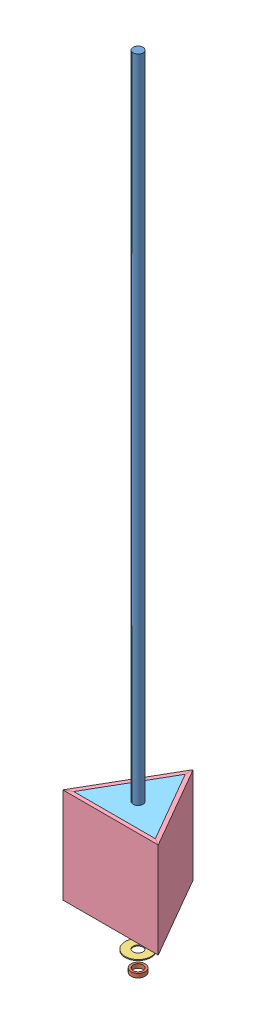
SolidWorks assembly rod_exploded, configuration Default. Lengths in mm.
Overall size (348 2551.69 364.2).
15 component instances, 6 part files, 3 mates.
Components (placement in the parent):
- rod-1: rod [Default] at (977.2141 709.9151 2218.518) size (31.75 2438.4 31.75)
- collar-1: collar [Default] at (977.2141 596.6255 2218.518) size (44.45 12.7 44.45)
- washer-1: washer [Default] at (977.2141 657.9856 2218.518) size (82.55 3.17 82.55)
- triangle-1: triangle [Default] at (859.8458 526.0056 2574.5415) x (1 0 0) z (0 1 0) size (348 364.2 304.8)
  - triangle_face-1: triangle_face [Default] at (-35.0317 268.0353 238.4474) size (304.8 12.7 304.8)
  - triangle_face-2: triangle_face [Default] at (117.3683 531.9998 238.4474) x (-0.5 -0.866025 0) z (0 0 1) size (304.8 12.7 304.8)
  - triangle_face-3: triangle_face [Default] at (269.7683 268.0353 238.4474) x (-0.5 0.866025 0) z (0 0 1) size (304.8 12.7 304.8)
  - triangle_top_bot-1: triangle_top_bot [Default] at (269.7683 268.0353 238.4474) x (0.5 -0.866025 0) z (0 0 -1) size (260.81 225.86 12.7)
  - triangle_top_bot-2: triangle_top_bot [Default] at (269.7683 268.0353 543.2474) size (260.81 225.86 12.7)
  - triangle_inside_corner-1: triangle_inside_corner [Default] at (53.355 472.7151 492.4474) x (0.5 -0.866025 0) z (-0.866025 -0.5 0) size (83.58 38.1 72.38)
  - triangle_inside_corner-2: triangle_inside_corner [Default] at (48.317 242.2404 492.4474) x (0.5 0.866025 0) z (0.866025 -0.5 0) size (83.58 38.1 72.38)
  - triangle_inside_corner-3: triangle_inside_corner [Default] at (225.5462 242.2404 492.4474) x (0.5 0.866025 0) z (0.866025 -0.5 0) size (83.58 38.1 72.38)
  - triangle_inside_corner-4: triangle_inside_corner [Default] at (48.317 242.2404 251.1474) x (0.5 0.866025 0) z (0.866025 -0.5 0) size (83.58 38.1 72.38)
  - triangle_inside_corner-6: triangle_inside_corner [Default] at (225.5462 242.2404 251.1474) x (0.5 0.866025 0) z (0.866025 -0.5 0) size (83.58 38.1 72.38)
  - triangle_inside_corner-7: triangle_inside_corner [Default] at (53.355 472.7151 251.1474) x (0.5 -0.866025 0) z (-0.866025 -0.5 0) size (83.58 38.1 72.38)
Mates (geometry in assembly coordinates):
- Concentric1: concentric aligned: circle of collar-1; circle of washer-1
- Concentric2: concentric aligned: circle of rod-1; circle of washer-1
- Concentric3: concentric anti-aligned: circle of rod-1; circle of triangle-1/triangle_top_bot-1
